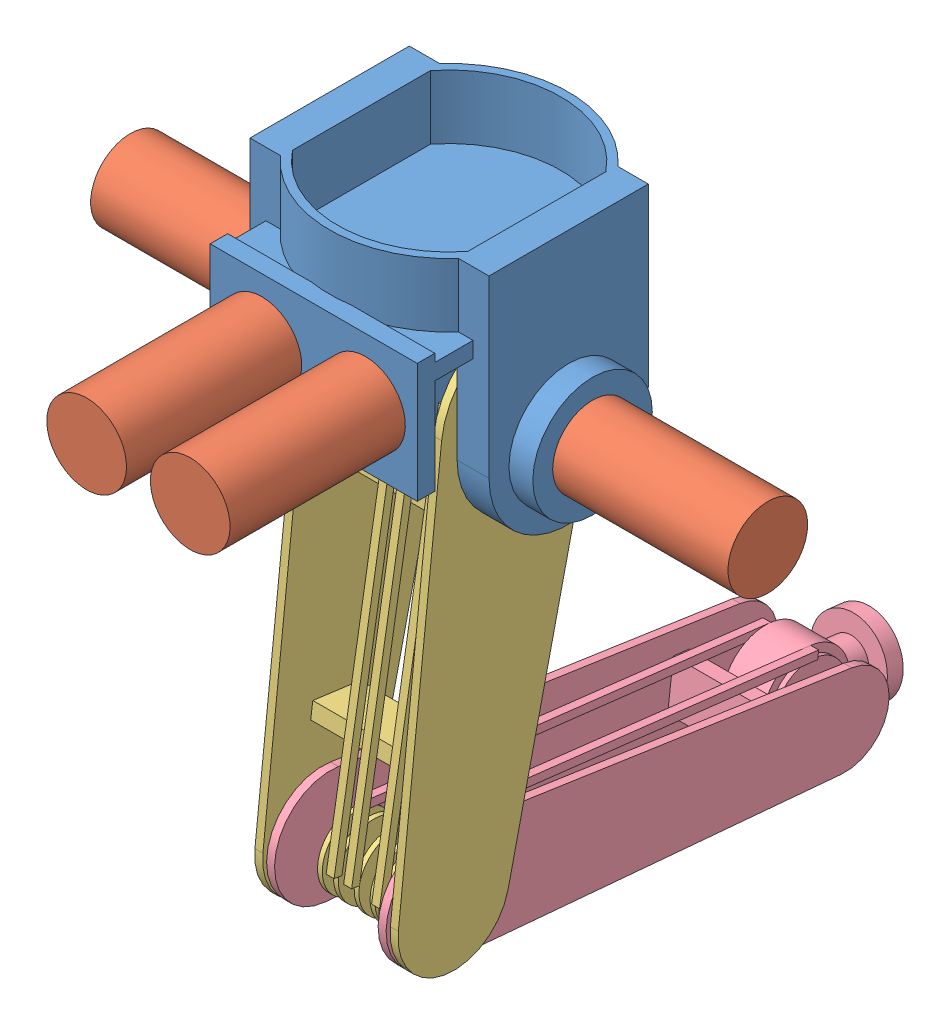
SolidWorks assembly J1J2J3wMotors, configuration Default. Lengths in mm.
Overall size (400 432.14 459.91).
7 component instances, 4 part files, 12 mates.
Components (placement in the parent):
- J1-1: J1 [Default] at (79.4739 128.2435 123.755) size (180 160 160)
- motor-1: motor [Default] at (-10.5261 68.2435 123.755) x (0 1 0) z (0 0 1) size (50 110 50)
- motor-2: motor [Default] at (46.9739 105.7435 208.755) x (1 0 0) z (0 -1 0) size (50 110 50)
- motor-3: motor [Default] at (111.9739 105.7435 208.755) x (1 0 0) z (0 -1 0) size (50 110 50)
- motor-4: motor [Default] at (279.4739 68.2435 123.755) x (0 1 0) z (0 0 1) size (50 110 50)
- J2-1: J2 [Default] at (34.4739 -122.1479 311.0365) x (0 -0.991066 0.133371) z (1 0 0) size (339.87 100 90)
- J3-1: J3 [Default] at (116.9739 -183.2596 165.8405) x (0 -0.11764 -0.993056) z (-1 0 0) size (340 70 75)
Mates (geometry in assembly coordinates):
- Coincident1: coincident anti-aligned: plane of J1-1 through (-10.5261 68.2435 123.755) normal (-1 0 0); plane of motor-1 through (-10.5261 68.2435 123.755) normal (1 0 0)
- Concentric2: concentric aligned: circle of J1-1; circle of motor-1
- Coincident2: coincident anti-aligned: plane of J1-1 through (169.4739 68.2435 123.755) normal (1 0 0); plane of motor-4 through (169.4739 68.2435 123.755) normal (-1 0 0)
- Concentric3: concentric anti-aligned: circle of J1-1; circle of motor-4
- Coincident3: coincident anti-aligned: plane of J1-1 through (79.4739 128.2435 208.755) normal (0 0 1); plane of motor-2 through (46.9739 105.7435 208.755) normal (0 0 -1)
- Coincident4: coincident anti-aligned: plane of J1-1 through (79.4739 128.2435 208.755) normal (0 0 1); plane of motor-3 through (111.9739 105.7435 208.755) normal (0 0 -1)
- Concentric4: concentric aligned: circle of motor-3; circle of assembly
- Concentric5: concentric aligned: circle of motor-2; circle of assembly
- Concentric6: concentric anti-aligned: circle of J1-1; circle of J2-1
- Distance1: distance = 10 mm anti-aligned: plane of J1-1 through (134.4739 68.2435 73.755) normal (-1 0 0); plane of J2-1 through (124.4739 68.2435 123.755) normal (1 0 0)
- Concentric7: concentric aligned: circle of J2-1; circle of J3-1
- Distance2: distance = 2.5 mm anti-aligned: plane of J3-1 through (116.9739 -183.2596 165.8405) normal (1 0 0); plane of J2-1 through (119.4739 -191.0567 131.72) normal (-1 0 0)
